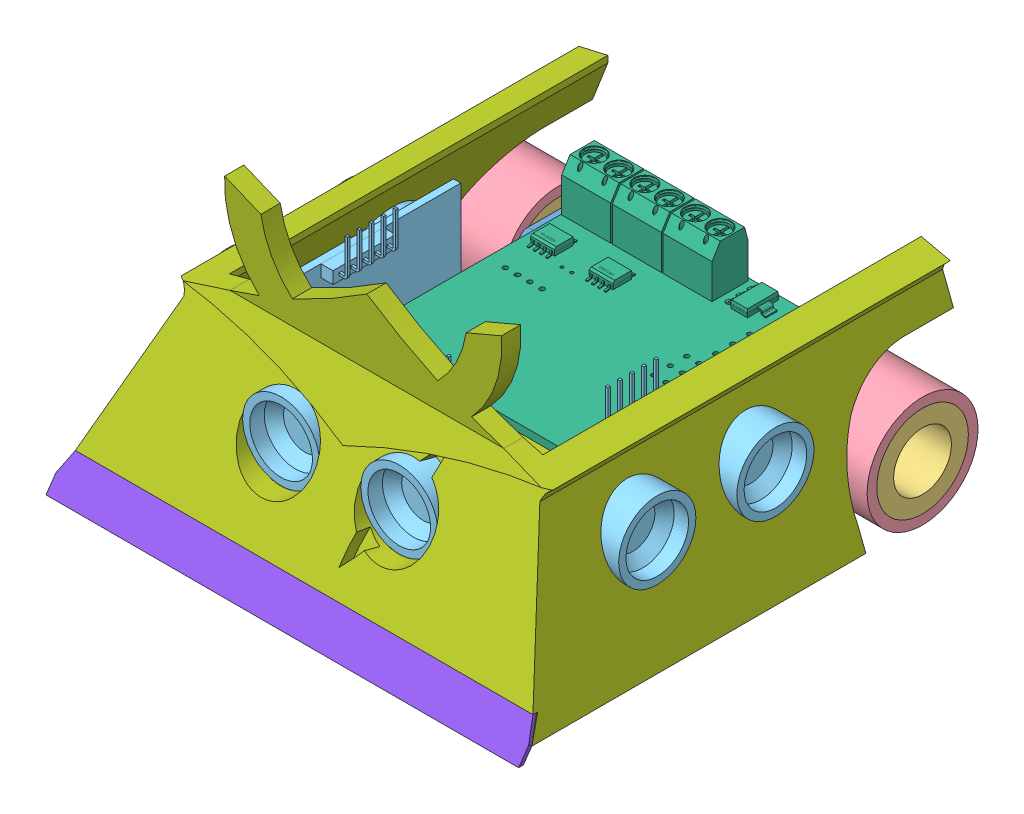
SolidWorks assembly Laberinto_G2, configuration Predeterminado. Lengths in mm.
Overall size (98 58.25 100).
16 component instances, 10 part files, 47 mates.
Components (placement in the parent):
- Guia_G2-1: Guia_G2 [Predeterminado] x (1 0 0) z (0 1 0) size (100 100 3) (hidden)
- Chasis_G2-1: Chasis_G2 [Predeterminado] at (0 3 0) x (1 0 0) z (0 1 0) size (98 98 33.62) (hidden)
- Soporte_Motor_Pololu-2: Soporte_Motor_Pololu [Predeterminado] at (22 7 14.55) x (0 0 -1) z (0 -1 0) size (29.1 14 12.6)
- MicroMotor_500RPM-1: MicroMotor_500RPM [Predeterminado] at (69.9977 -13.8 19.5263) x (0 0 1) z (0 1 0) size (12 34.8 10) (hidden)
- Soporte_Motor_Pololu-3: Soporte_Motor_Pololu [Predeterminado] at (78 7 14.55) x (0 0 1) z (0 -1 0) size (29.1 14 12.6)
- MicroMotor_500RPM-2: MicroMotor_500RPM [Predeterminado] at (30.0023 37.8 19.5263) x (0 0 1) z (0 -1 0) size (12 34.8 10)
- Llanta_V2-1: Llanta_V2 [Predeterminado] at (78.3 12 14.55) x (0 0.004307 -0.999991) z (1 0 0) size (19 19 19)
- Llanta_V2-2: Llanta_V2 [Predeterminado] at (21.7 12 14.55) x (0 0 1) z (-1 0 0) size (19 19 19)
- Cubierta_V2-1: Cubierta_V2 [Predeterminado] at (97.3 12 14.55) x (0 0 -1) z (1 0 0) size (23 23 19)
- Cubierta_V2-2: Cubierta_V2 [Predeterminado] at (21.7 12 14.55) x (0 0 -1) z (1 0 0) size (23 23 19)
- UltraSonic_Sensor-1: UltraSonic_Sensor [Default] at (50 21.25 74.5) x (-1 0 0) z (0 0 1) size (45 26.75 17.75)
- UltraSonic_Sensor-5: UltraSonic_Sensor [Default] at (81 21.25 54.5) x (0 0 1) z (1 0 0) size (45 26.75 17.75)
- UltraSonic_Sensor-6: UltraSonic_Sensor [Default] at (19 21.25 54.5) x (0 0 -1) z (-1 0 0) size (45 26.75 17.75)
- RobotLaberintoG2_PCB-1: RobotLaberintoG2_PCB [Predeterminado] at (184.8218 19.8111 139.0787) x (-1 0 0) z (0 1 0) size (50 50 13.05)
- Chasis_G2V1-1: Chasis_G2V1 [Predeterminado] at (0 3 0) x (-1 0 0) z (0 -1 0) size (98 97.26 55.75)
- Cuchilla_G2-2: Cuchilla_G2 [Predeterminado] at (22 3 0) x (0 1 0) z (-1 0 0) size (6.5 5.53 98)
Mates (geometry in assembly coordinates):
- EnPosición1: in place: plane of Guia_G2-1 through (0 0 0) normal (0 1 0); moOrthogonalPlaneRef_w of Guia_G2-1 through (0 0 0) normal (0 0 -1); plane of Guia_G2-1 through (0 0 0) normal (1 0 0); unknown of Guia_G2-1
- Coincidente1: coincident: plane of assembly; plane of Guia_G2-1; plane of assembly
- Coincidente2: coincident: plane of Pieza1^Ensamblaje1-1 through (0 0 0) normal (0 0 -1)
- Coincidente3: coincident: plane of Pieza1^Ensamblaje1-1 through (0 0 0) normal (1 0 0)
- EnPosición2: in place: plane of Guia_G2-1 through (0 3 0) normal (0 1 0); plane of Chasis_G2-1 through (0 3 0) normal (0 1 0); plane of Guia_G2-1 through (0 3 0) normal (0 1 0); plane of Chasis_G2-1 through (0 3 0) normal (0 0 -1); plane of Guia_G2-1 through (0 3 0) normal (0 1 0); plane of Chasis_G2-1 through (0 3 0) normal (1 0 0); plane of Guia_G2-1 through (0 3 0) normal (0 1 0); unknown of Chasis_G2-1
- Coincidente4: coincident: plane of Guia_G2-1; plane of Chasis_G2-1
- Coincidente5: coincident: moOrthogonalPlaneRef_w of Guia_G2-1 through (0 3 0) normal (0 0 -1); plane of Chasis_G2-1 through (0 3 0) normal (0 0 -1)
- Coincidente6: coincident: moOrthogonalPlaneRef_w of Guia_G2-1 through (0 3 0) normal (-1 0 0); plane of Chasis_G2-1 through (0 3 0) normal (1 0 0)
- Distancia2: distance = 0 mm: plane of Soporte_Motor_Pololu-2 through (36 7 0) normal (0 0 -1); plane of Chasis_G2-1 through (78 7 0) normal (0 0 -1)
- Distancia4: distance = 0 mm: plane of Soporte_Motor_Pololu-2 through (22 7 14.55) normal (-1 0 0); plane of Chasis_G2-1 through (22 7 0) normal (-1 0 0)
- Distancia6: distance = 0 mm: plane of Soporte_Motor_Pololu-2 through (36 7 14.55) normal (0 -1 0); plane of Chasis_G2-1 through (0 7 0) normal (0 1 0)
- Distancia7: distance = 0 mm: plane of Soporte_Motor_Pololu-3 through (64 7 14.55) normal (0 -1 0); plane of Chasis_G2-1 through (0 7 0) normal (0 1 0)
- Distancia8: distance = 0 mm: plane of Soporte_Motor_Pololu-3 through (64 7 0) normal (0 0 -1); plane of Chasis_G2-1 through (78 7 0) normal (0 0 -1)
- Distancia9: distance = 0 mm: plane of Chasis_G2-1 through (78 7 0) normal (1 0 0); plane of Soporte_Motor_Pololu-3 through (78 7 14.55) normal (1 0 0)
- Distancia10: distance = 0 mm: plane of MicroMotor_500RPM-1 through (78 12 14.55) normal (1 0 0); plane of Soporte_Motor_Pololu-3 through (78 7 14.55) normal (1 0 0)
- Distancia11: distance = 0 mm: plane of MicroMotor_500RPM-1 through (78 7 8.55) normal (0 -1 0); plane of Chasis_G2-1 through (0 7 0) normal (0 1 0)
- Distancia12: distance = 0.05 mm: plane of MicroMotor_500RPM-1 through (78 7 20.55) normal (0 0 1); plane of Soporte_Motor_Pololu-3 through (64 7 20.6) normal (0 0 -1)
- Distancia13: distance = 0 mm: plane of MicroMotor_500RPM-2 through (22 12 14.55) normal (-1 0 0); plane of Soporte_Motor_Pololu-2 through (22 7 14.55) normal (-1 0 0)
- Distancia14: distance = 0 mm: plane of MicroMotor_500RPM-2 through (22 7 20.55) normal (0 -1 0); plane of Chasis_G2-1 through (0 7 0) normal (0 1 0)
- Distancia15: distance = 0.05 mm: plane of Soporte_Motor_Pololu-2 through (36 7 20.6) normal (0 0 -1); plane of MicroMotor_500RPM-2 through (22 17 20.55) normal (0 0 1)
- Concéntrica1: concentric: cylinder of MicroMotor_500RPM-1 through (87.3 12 14.55) axis (-1 0 0) radius 1.5; cylinder of Llanta_V2-1 through (97.3 12 14.55) axis (-1 0 0) radius 1.625
- Distancia17: distance = 0 mm: plane of Llanta_V2-2 through (21.7 12 14.55) normal (1 0 0); plane of MicroMotor_500RPM-2 through (21.7 12 14.55) normal (-1 0 0)
- Concéntrica2: concentric: cylinder of MicroMotor_500RPM-2 through (12.7 12 14.55) axis (1 0 0) radius 1.5; cylinder of Llanta_V2-2 through (2.7 12 14.55) axis (1 0 0) radius 1.625
- Distancia18: distance = 0 mm: plane of MicroMotor_500RPM-1 through (78.3 12 14.55) normal (1 0 0); plane of Llanta_V2-1 through (78.3 12 14.55) normal (-1 0 0)
- Concéntrica3: concentric: cylinder of Llanta_V2-1 through (95.3 12 14.55) axis (1 0 0) radius 9.5; cylinder of Cubierta_V2-1 through (78.3 12 14.55) axis (1 0 0) radius 9.5
- Distancia19: distance = 0 mm: plane of Llanta_V2-1 through (97.3 12 14.55) normal (1 0 0); plane of Cubierta_V2-1 through (97.3 12 14.55) normal (1 0 0)
- Distancia20: distance = 0 mm: plane of Cubierta_V2-2 through (2.7 12 14.55) normal (-1 0 0); plane of Llanta_V2-2 through (2.7 12 14.55) normal (-1 0 0)
- Concéntrica4: concentric: cylinder of Llanta_V2-2 through (4.7 12 14.55) axis (-1 0 0) radius 9.5; cylinder of Cubierta_V2-2 through (2.7 12 14.55) axis (1 0 0) radius 9.5
- Distancia21: distance = 10 mm: plane of UltraSonic_Sensor-1 through (62.25 22.5 88) normal (0 0 1); plane of Chasis_G2-1 through (99 7 98) normal (0 0 1)
- Distancia22: distance = 4 mm: plane of UltraSonic_Sensor-5 through (82.5 11 32) normal (0 -1 0); plane of Chasis_G2-1 through (0 7 0) normal (0 1 0)
- Distancia23: distance = 4 mm: plane of UltraSonic_Sensor-6 through (17.5 11 77) normal (0 -1 0); plane of Chasis_G2-1 through (0 7 0) normal (0 1 0)
- Distancia24: distance = 4 mm: plane of UltraSonic_Sensor-6 through (17.5 11 32) normal (0 0 -1); plane of Chasis_G2-1 through (1 7 28) normal (0 0 -1)
- Distancia25: distance = 4 mm: plane of Chasis_G2-1 through (99 7 28) normal (0 0 -1); plane of UltraSonic_Sensor-5 through (82.5 11 32) normal (0 0 -1)
- Distancia28: distance = 4 mm: plane of UltraSonic_Sensor-1 through (72.5 11 76) normal (0 -1 0); plane of Chasis_G2-1 through (0 7 0) normal (0 1 0)
- Distancia29: distance = 26.5 mm: plane of UltraSonic_Sensor-1 through (27.5 11 76) normal (-1 0 0); plane of Chasis_G2-1 through (1 7 98) normal (-1 0 0)
- EnPosición3: in place: plane of Chasis_G2-1 through (0 3 0) normal (0 -1 0); plane of Chasis_G2V1-1 through (0 3 0) normal (0 -1 0); plane of Chasis_G2-1 through (0 3 0) normal (0 -1 0); plane of Chasis_G2V1-1 through (0 3 0) normal (0 0 -1); plane of Chasis_G2-1 through (0 3 0) normal (0 -1 0); plane of Chasis_G2V1-1 through (0 3 0) normal (-1 0 0); plane of Chasis_G2-1 through (0 3 0) normal (0 -1 0); unknown of Chasis_G2V1-1
- Coincidente1: coincident: plane of Chasis_G2-1; plane of Chasis_G2V1-1
- Coincidente2: coincident: moOrthogonalPlaneRef_w of Chasis_G2-1 through (0 3 0) normal (0 0 -1); plane of Chasis_G2V1-1 through (0 3 0) normal (0 0 -1)
- Coincidente3: coincident: moOrthogonalPlaneRef_w of Chasis_G2-1 through (0 3 0) normal (1 0 0); plane of Chasis_G2V1-1 through (0 3 0) normal (-1 0 0)
- EnPosición4: in place: plane of Chasis_G2V1-1 through (99 7 95.4746) normal (0 0.571375 0.820689); plane of ? through (0 47.0553 67.5876) normal (0 0.571375 0.820689); plane of Chasis_G2V1-1 through (99 7 95.4746) normal (0 0.571375 0.820689); plane of ? through (0 47.0553 67.5876) normal (0 0.820689 -0.571375); plane of Chasis_G2V1-1 through (99 7 95.4746) normal (0 0.571375 0.820689); plane of ? through (0 47.0553 67.5876) normal (1 0 0); plane of Chasis_G2V1-1 through (99 7 95.4746) normal (0 0.571375 0.820689); unknown of ?
- Coincidente1: coincident: plane of Chasis_G2V1-1; plane of ?
- Coincidente2: coincident: moOrthogonalPlaneRef_w of Chasis_G2V1-1 through (0 49.0759 66.1808) normal (0 0.820689 -0.571375); plane of Pieza1^Laberinto_G2-1 through (0 49.0759 66.1808) normal (0 0.820689 -0.571375)
- Coincidente3: coincident: moOrthogonalPlaneRef_w of Chasis_G2V1-1 through (0 49.0759 66.1808) normal (-1 0 0); plane of Pieza1^Laberinto_G2-1 through (0 49.0759 66.1808) normal (1 0 0)
- EnPosición5: in place: plane of Chasis_G2V1-1 through (22 7 28) normal (-1 0 0); plane of ? through (22 0 0) normal (-1 0 0); plane of Chasis_G2V1-1 through (22 7 28) normal (-1 0 0); plane of ? through (22 0 0) normal (0 1 0); plane of Chasis_G2V1-1 through (22 7 28) normal (-1 0 0); plane of ? through (22 0 0) normal (0 0 1); plane of Chasis_G2V1-1 through (22 7 28) normal (-1 0 0); unknown of Cuchilla_G2-2
- Coincidente1: coincident: plane of Chasis_G2V1-1; plane of Cuchilla_G2-2
- Coincidente2: coincident: moOrthogonalPlaneRef_w of Chasis_G2V1-1 through (22 3 0) normal (0 0 -1); plane of Cuchilla_G2-2 through (22 3 0) normal (0 0 -1)
- Coincidente3: coincident: moOrthogonalPlaneRef_w of Chasis_G2V1-1 through (22 3 0) normal (0 -1 0); plane of Cuchilla_G2-2 through (22 3 0) normal (0 1 0)
